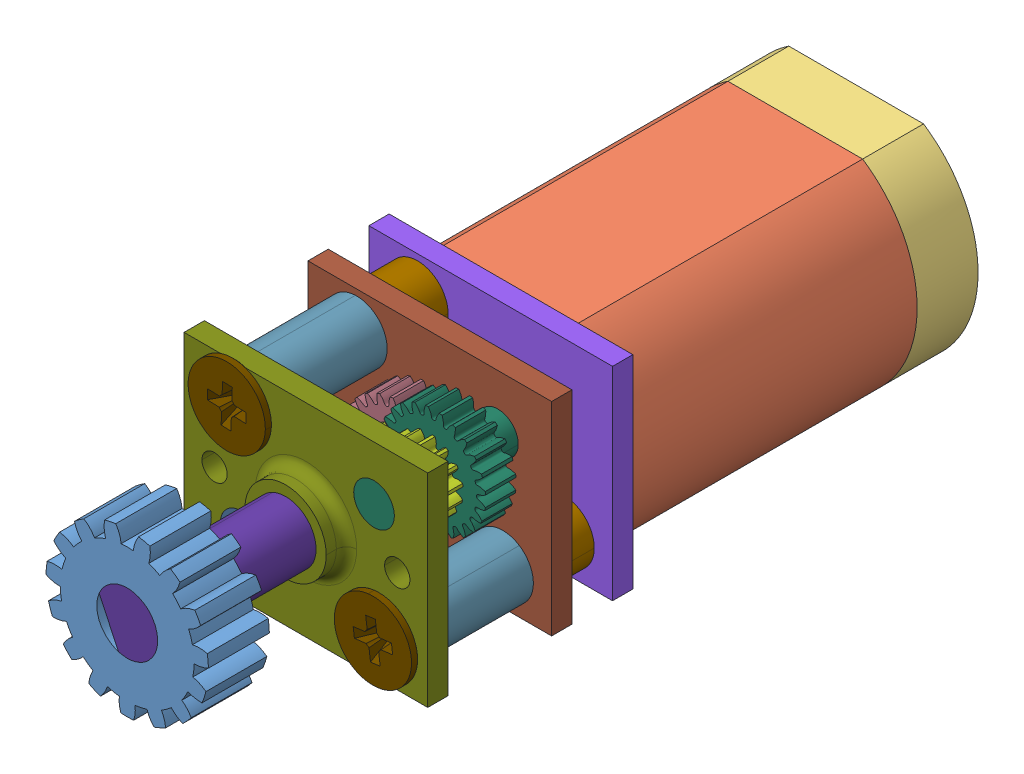
SolidWorks assembly Assem4, configuration Default. Lengths in mm.
Overall size (12.54 10.71 36.76).
25 component instances, 18 part files, 2 mates.
Components (placement in the parent):
- Part8-1: Part8 [Default] at (-16.9364 23.0827 65.0916) size (8 7.96 3)
- part3-2: part3 [Default] at (-16.9364 23.0827 42.1916) x (0 0 -1) z (-1 0 0) size (36.76 10.71 12.54)
  - GA12-N20 Motor.IGS-1: GA12-N20 Motor.IGS [Default] at origin size (36.76 10.71 12.54)
    - Motor Case.IGS-1: Motor Case.IGS [Default] at origin size (14.01 10.01 12.01)
    - Rear Cover.IGS-1: Rear Cover.IGS [Default] at (7 0 0) size (5.9 10.01 12.01)
    - Rear Bearing.IGS-1: Rear Bearing.IGS [Default] at (8.5 0 0) x (1 0 0) z (0 -0.26494 0.964265) size (3.01 5.01 5.01)
    - Front Bearing.IGS-1: Front Bearing.IGS [Default] at (-5.5 0 0) size (1.51 4.01 4.01)
    - Rotor.IGS-1: Rotor.IGS [Default] at (7 0 0) x (1 0 0) z (0 -0.999982 -0.005961) size (16.73 7.6 7.6)
    - Spur 1-15_Spur01.IGS-1: Spur 1-15_Spur01.IGS [Default] at (-8.95 0 0) x (0 0.938794 -0.344479) z (1 0 0) size (3.39 3.4 1.51)
    - Spur 1-15_Spur01.IGS-2: Spur 1-15_Spur01.IGS [Default] at (-13.45 -0.1537 -0.1366) x (0 0.907 -0.421131) z (1 0 0) size (3.39 3.4 1.51)
    - Spur 1-15_Spur01.IGS-3: Spur 1-15_Spur01.IGS [Default] at (-15.15 -2.3556 -3.3556) x (0 0.43824 -0.898858) z (1 0 0) size (3.39 3.4 1.51)
    - Plate 1.IGS-1: Plate 1.IGS [Default] at (-8 0 0) x (0 0 -1) z (1 0 0) size (12.01 10.01 1.01)
    - Stand 2.IGS-1: Stand 2.IGS [Default] at (-10 3.2 -3.6) size (2.01 3.01 3.01)
    - Stand 2.IGS-2: Stand 2.IGS [Default] at (-10 -3.2 3.6) size (2.01 3.01 3.01)
    - Spur 2-24_Spur01.IGS-1: Spur 2-24_Spur01.IGS [Default] at (-8.95 2.212 3.212) x (0 -0.938774 -0.344534) z (-1 0 0) size (5.18 5.18 10.41)
    - Plate 2.IGS-1: Plate 2.IGS [Default] at (-11 0 0) x (0 0 -1) z (1 0 0) size (12.01 10.01 1.01)
    - Spur 2-15_Spur01.IGS-1: Spur 2-15_Spur01.IGS [Default] at (-11.2 2.212 3.212) x (0 0.605236 0.796046) z (1 0 0) size (3.39 3.4 3.01)
    - Spur 1-26_Spur01.IGS-1: Spur 1-26_Spur01.IGS [Default] at (-11.95 -0.1537 -0.1366) x (0 -0.999955 -0.009462) z (-1 0 0) size (5.58 5.61 4.21)
    - Stand 4.IGS-1: Stand 4.IGS [Default] at (-16.1 3.2 -3.6) x (1 0 0) z (0 0.841922 0.539599) size (5.11 3.01 3.01)
    - Stand 4.IGS-2: Stand 4.IGS [Default] at (-16.1 -3.2 3.6) x (1 0 0) z (0 -0.999156 0.041072) size (5.11 3.01 3.01)
    - Spur 1-24_Spur01.IGS-1: Spur 1-24_Spur01.IGS [Default] at (-13.45 -2.3556 -3.3556) x (0 -0.016431 0.999865) z (1 0 0) size (5.18 5.18 7.11)
    - Plate 3.IGS-1: Plate 3.IGS [Default] at (-16.1 0 0) x (0 0 -1) z (-1 0 0) size (12.01 10.21 2.01)
    - Spur 2-26_Spur01.IGS-1: Spur 2-26_Spur01.IGS [Default] at (-15.15 0 0) x (0 0.905811 -0.423682) z (1 0 0) size (5.58 5.61 11.51)
    - countersunk flat head cross recess screw_iso_ISO 7046-1 - M2 x 12 - Z --- 12N.IGS-1: countersunk flat head cross recess screw_iso_ISO 7046-1 - M2 x 12 - Z --- 12N.IGS [Default] at (-17.4 -3.2 3.6) x (1 0 0) z (0 -0.036501 0.999334) size (12.01 3.81 3.81)
    - countersunk flat head cross recess screw_iso_ISO 7046-1 - M2 x 12 - Z --- 12N.IGS-2: countersunk flat head cross recess screw_iso_ISO 7046-1 - M2 x 12 - Z --- 12N.IGS [Default] at (-17.4 3.2 -3.6) x (1 0 0) z (0 -0.992044 0.125888) size (12.01 3.81 3.81)
Mates (geometry in assembly coordinates):
- Tangent3: tangent aligned: cylinder of Part8-1 through (-16.9364 23.0827 65.0916) axis (0 0 1) radius 1.5; face of part3-2/GA12-N20 Motor.IGS-1/Spur 2-26_Spur01.IGS-1
- Tangent4: tangent aligned: plane of Part8-1 through (-16.9364 23.0827 68.0916) normal (0 0 1); edge_curve of part3-2/GA12-N20 Motor.IGS-1/Spur 2-26_Spur01.IGS-1
